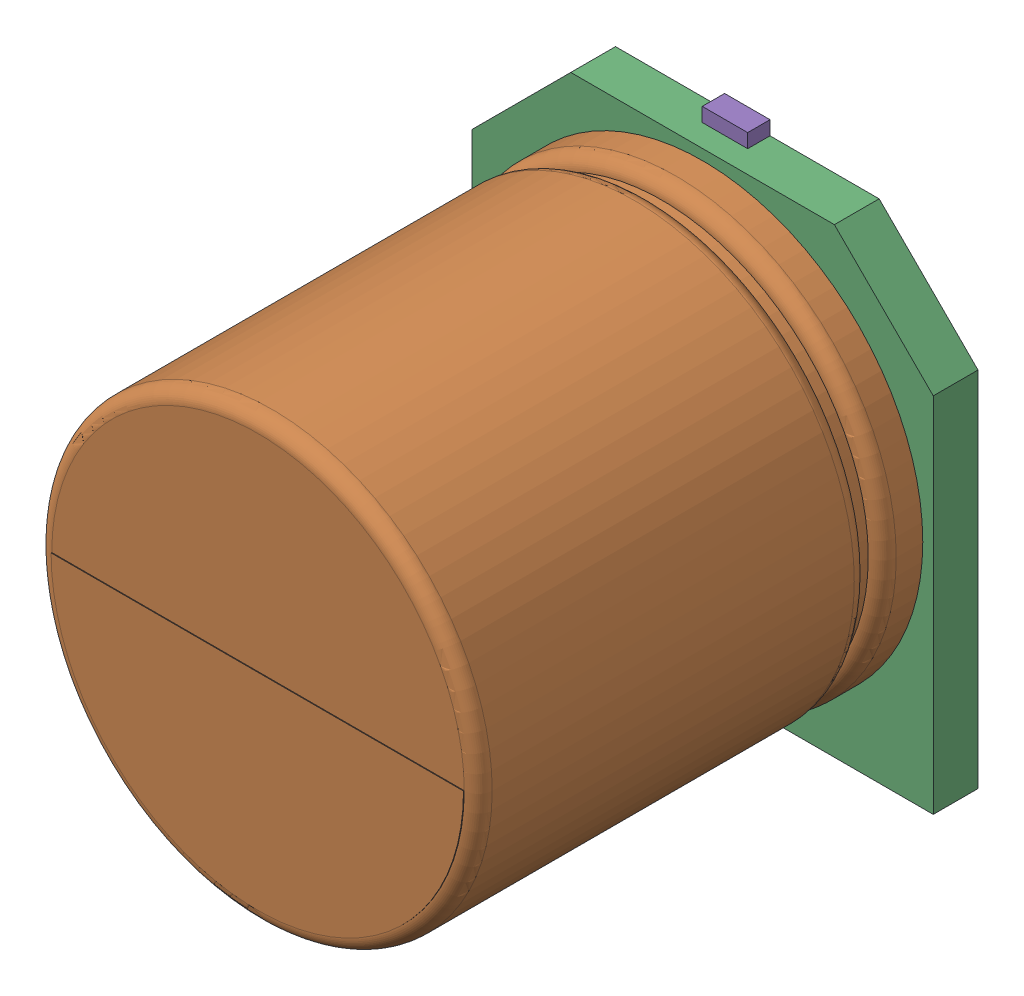
SolidWorks assembly C29, configuration Default. Lengths in mm.
Overall size (6.6 7 7.01).
6 component instances, 5 part files, 0 mates.
Components (placement in the parent):
- User_Library-CAPSMD6_3x7-1: User_Library-CAPSMD6_3x7 [Default] at (80.5194 27.0821 0) x (1 0 0) z (0 0 1) size (6.6 7 7.01)
  - User_Library-CAPSMD6_3x3_9_CAP003-1: User_Library-CAPSMD6_3x3_9_CAP003 [Default] at origin size (0.65 2.6 0.32)
  - User_Library-CAPSMD6_3x3_9_CAP-1: User_Library-CAPSMD6_3x3_9_CAP [Default] at origin size (6.3 6.3 6.37)
  - User_Library-CAPSMD6_3x3_9_CAP001-1: User_Library-CAPSMD6_3x3_9_CAP001 [Default] at origin size (6.6 6.6 0.64)
  - User_Library-CAPSMD6_3x3_9_CAP002-1: User_Library-CAPSMD6_3x3_9_CAP002 [Default] at origin size (5.11 1.47 0.01)
  - User_Library-CAPSMD6_3x3_9_CAP004-1: User_Library-CAPSMD6_3x3_9_CAP004 [Default] at origin size (0.65 2.6 0.32)
